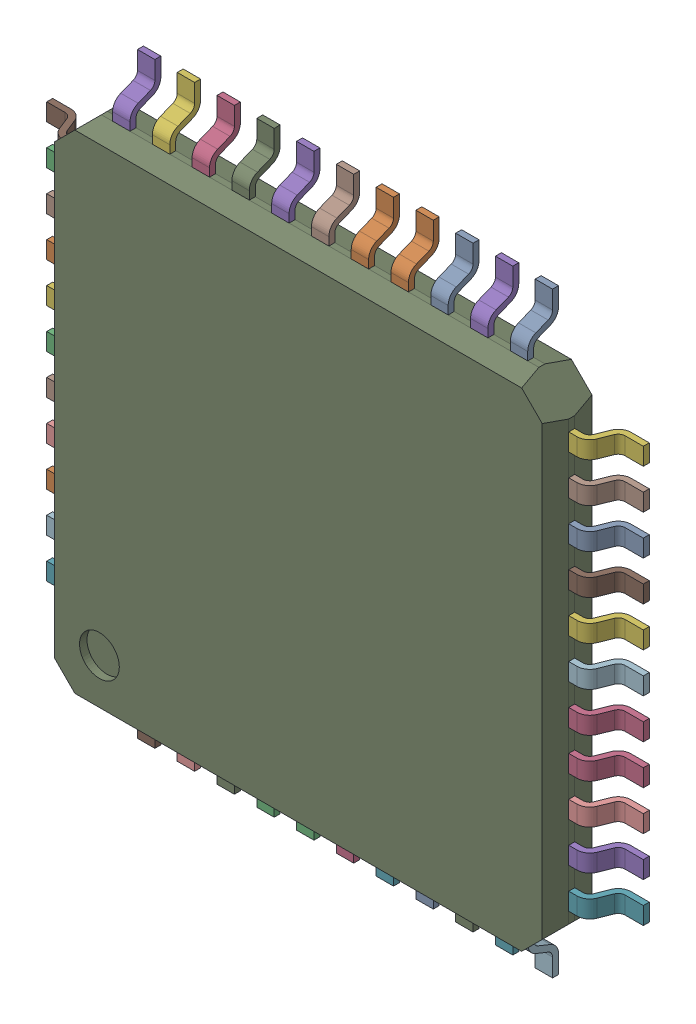
SolidWorks assembly U1, configuration Défaut. Lengths in mm.
Overall size (12 12 1.06).
46 component instances, 2 part files, 0 mates.
Components (placement in the parent):
- User_Library-TQFP-44-1: User_Library-TQFP-44 [Défaut] at (21.4631 42.8961 0.55) size (12 12 1.06)
  - User_Library-TQFP-44_pins_TQFP_pin_TQFP_035_1-1: User_Library-TQFP-44_pins_TQFP_pin_TQFP_035_1 [Défaut] at (6 2.225 -0.5) x (0 1 0) z (1 0 0) size (0.35 0.62 1)
  - User_Library-TQFP-44_pins_TQFP_pin_TQFP_035_1-2: User_Library-TQFP-44_pins_TQFP_pin_TQFP_035_1 [Défaut] at (-6 -2.225 -0.5) x (0 -1 0) z (-1 0 0) size (0.35 0.62 1)
  - User_Library-TQFP-44_pins_TQFP_pin_TQFP_035_1-3: User_Library-TQFP-44_pins_TQFP_pin_TQFP_035_1 [Défaut] at (-6 3.375 -0.5) x (0 -1 0) z (-1 0 0) size (0.35 0.62 1)
  - User_Library-TQFP-44_pins_TQFP_pin_TQFP_035_1-4: User_Library-TQFP-44_pins_TQFP_pin_TQFP_035_1 [Défaut] at (6 -0.975 -0.5) x (0 1 0) z (1 0 0) size (0.35 0.62 1)
  - User_Library-TQFP-44_pins_TQFP_pin_TQFP_035_1-5: User_Library-TQFP-44_pins_TQFP_pin_TQFP_035_1 [Défaut] at (3.375 6 -0.5) x (-1 0 0) z (0 1 0) size (0.35 0.62 1)
  - User_Library-TQFP-44_pins_TQFP_pin_TQFP_035_1-6: User_Library-TQFP-44_pins_TQFP_pin_TQFP_035_1 [Défaut] at (-6 0.975 -0.5) x (0 -1 0) z (-1 0 0) size (0.35 0.62 1)
  - User_Library-TQFP-44_pins_TQFP_pin_TQFP_035_1-7: User_Library-TQFP-44_pins_TQFP_pin_TQFP_035_1 [Défaut] at (0.625 -6 -0.5) x (1 0 0) z (0 -1 0) size (0.35 0.62 1)
  - User_Library-TQFP-44_pins_TQFP_pin_TQFP_035_1-8: User_Library-TQFP-44_pins_TQFP_pin_TQFP_035_1 [Défaut] at (0.175 6 -0.5) x (-1 0 0) z (0 1 0) size (0.35 0.62 1)
  - User_Library-TQFP-44_pins_TQFP_pin_TQFP_035_1-9: User_Library-TQFP-44_pins_TQFP_pin_TQFP_035_1 [Défaut] at (-2.575 -6 -0.5) x (1 0 0) z (0 -1 0) size (0.35 0.62 1)
  - User_Library-TQFP-44_pins_TQFP_pin_TQFP_035_1-10: User_Library-TQFP-44_pins_TQFP_pin_TQFP_035_1 [Défaut] at (-3.375 -6 -0.5) x (1 0 0) z (0 -1 0) size (0.35 0.62 1)
  - User_Library-TQFP-44_pins_TQFP_pin_TQFP_035_1-11: User_Library-TQFP-44_pins_TQFP_pin_TQFP_035_1 [Défaut] at (6 1.425 -0.5) x (0 1 0) z (1 0 0) size (0.35 0.62 1)
  - User_Library-TQFP-44_pins_TQFP_pin_TQFP_035_1-12: User_Library-TQFP-44_pins_TQFP_pin_TQFP_035_1 [Défaut] at (-6 -3.025 -0.5) x (0 -1 0) z (-1 0 0) size (0.35 0.62 1)
  - User_Library-TQFP-44_pins_TQFP_pin_TQFP_035_1-13: User_Library-TQFP-44_pins_TQFP_pin_TQFP_035_1 [Défaut] at (2.575 6 -0.5) x (-1 0 0) z (0 1 0) size (0.35 0.62 1)
  - User_Library-TQFP-44_pins_TQFP_pin_TQFP_035_1-14: User_Library-TQFP-44_pins_TQFP_pin_TQFP_035_1 [Défaut] at (1.775 6 -0.5) x (-1 0 0) z (0 1 0) size (0.35 0.62 1)
  - User_Library-TQFP-44_pins_TQFP_pin_TQFP_035_1-15: User_Library-TQFP-44_pins_TQFP_pin_TQFP_035_1 [Défaut] at (-0.975 -6 -0.5) x (1 0 0) z (0 -1 0) size (0.35 0.62 1)
  - User_Library-TQFP-44_pins_TQFP_pin_TQFP_035_1-16: User_Library-TQFP-44_pins_TQFP_pin_TQFP_035_1 [Défaut] at (-0.175 -6 -0.5) x (1 0 0) z (0 -1 0) size (0.35 0.62 1)
  - User_Library-TQFP-44_pins_TQFP_pin_TQFP_035_1-17: User_Library-TQFP-44_pins_TQFP_pin_TQFP_035_1 [Défaut] at (-0.625 6 -0.5) x (-1 0 0) z (0 1 0) size (0.35 0.62 1)
  - User_Library-TQFP-44_pins_TQFP_pin_TQFP_035_1-18: User_Library-TQFP-44_pins_TQFP_pin_TQFP_035_1 [Défaut] at (-3.025 6 -0.5) x (-1 0 0) z (0 1 0) size (0.35 0.62 1)
  - User_Library-TQFP-44_pins_TQFP_pin_TQFP_035_1-19: User_Library-TQFP-44_pins_TQFP_pin_TQFP_035_1 [Défaut] at (6 -4.175 -0.5) x (0 1 0) z (1 0 0) size (0.35 0.62 1)
  - User_Library-TQFP-44_pins_TQFP_pin_TQFP_035_1-20: User_Library-TQFP-44_pins_TQFP_pin_TQFP_035_1 [Défaut] at (6 3.025 -0.5) x (0 1 0) z (1 0 0) size (0.35 0.62 1)
  - User_Library-TQFP-44_pins_TQFP_pin_TQFP_035_1-21: User_Library-TQFP-44_pins_TQFP_pin_TQFP_035_1 [Défaut] at (2.225 -6 -0.5) x (1 0 0) z (0 -1 0) size (0.35 0.62 1)
  - User_Library-TQFP-44_pins_TQFP_pin_TQFP_035_1-22: User_Library-TQFP-44_pins_TQFP_pin_TQFP_035_1 [Défaut] at (-6 -1.425 -0.5) x (0 -1 0) z (-1 0 0) size (0.35 0.62 1)
  - User_Library-TQFP-44_pins_TQFP_pin_TQFP_035_1-23: User_Library-TQFP-44_pins_TQFP_pin_TQFP_035_1 [Défaut] at (-6 4.175 -0.5) x (0 -1 0) z (-1 0 0) size (0.35 0.62 1)
  - User_Library-TQFP-44_pins_TQFP_pin_TQFP_035_1-24: User_Library-TQFP-44_pins_TQFP_pin_TQFP_035_1 [Défaut] at (6 -0.175 -0.5) x (0 1 0) z (1 0 0) size (0.35 0.62 1)
  - User_Library-TQFP-44_pins_TQFP_pin_TQFP_035_1-25: User_Library-TQFP-44_pins_TQFP_pin_TQFP_035_1 [Défaut] at (4.175 6 -0.5) x (-1 0 0) z (0 1 0) size (0.35 0.62 1)
  - User_Library-TQFP-44_pins_TQFP_pin_TQFP_035_1-26: User_Library-TQFP-44_pins_TQFP_pin_TQFP_035_1 [Défaut] at (-6 1.775 -0.5) x (0 -1 0) z (-1 0 0) size (0.35 0.62 1)
  - User_Library-TQFP-44_pins_TQFP_pin_TQFP_035_1-27: User_Library-TQFP-44_pins_TQFP_pin_TQFP_035_1 [Défaut] at (-6 0.175 -0.5) x (0 -1 0) z (-1 0 0) size (0.35 0.62 1)
  - User_Library-TQFP-44_pins_TQFP_pin_TQFP_035_1-28: User_Library-TQFP-44_pins_TQFP_pin_TQFP_035_1 [Défaut] at (6 -1.775 -0.5) x (0 1 0) z (1 0 0) size (0.35 0.62 1)
  - User_Library-TQFP-44_pins_TQFP_pin_TQFP_035_1-29: User_Library-TQFP-44_pins_TQFP_pin_TQFP_035_1 [Défaut] at (-3.825 6 -0.5) x (-1 0 0) z (0 1 0) size (0.35 0.62 1)
  - User_Library-TQFP-44_pins_TQFP_pin_TQFP_035_1-30: User_Library-TQFP-44_pins_TQFP_pin_TQFP_035_1 [Défaut] at (6 0.625 -0.5) x (0 1 0) z (1 0 0) size (0.35 0.62 1)
  - User_Library-TQFP-44_pins_TQFP_pin_TQFP_035_1-31: User_Library-TQFP-44_pins_TQFP_pin_TQFP_035_1 [Défaut] at (-6 -3.825 -0.5) x (0 -1 0) z (-1 0 0) size (0.35 0.62 1)
  - User_Library-TQFP-44_pins_TQFP_pin_TQFP_035_1-32: User_Library-TQFP-44_pins_TQFP_pin_TQFP_035_1 [Défaut] at (-6 2.575 -0.5) x (0 -1 0) z (-1 0 0) size (0.35 0.62 1)
  - User_Library-TQFP-44_pins_TQFP_pin_TQFP_035_1-33: User_Library-TQFP-44_pins_TQFP_pin_TQFP_035_1 [Défaut] at (-1.425 6 -0.5) x (-1 0 0) z (0 1 0) size (0.35 0.62 1)
  - User_Library-TQFP-44_pins_TQFP_pin_TQFP_035_1-34: User_Library-TQFP-44_pins_TQFP_pin_TQFP_035_1 [Défaut] at (6 -2.575 -0.5) x (0 1 0) z (1 0 0) size (0.35 0.62 1)
  - User_Library-TQFP-44_pins_TQFP_pin_TQFP_035_1-35: User_Library-TQFP-44_pins_TQFP_pin_TQFP_035_1 [Défaut] at (-4.175 -6 -0.5) x (1 0 0) z (0 -1 0) size (0.35 0.62 1)
  - User_Library-TQFP-44_pins_TQFP_pin_TQFP_035_1-36: User_Library-TQFP-44_pins_TQFP_pin_TQFP_035_1 [Défaut] at (3.825 -6 -0.5) x (1 0 0) z (0 -1 0) size (0.35 0.62 1)
  - User_Library-TQFP-44_pins_TQFP_pin_TQFP_035_1-37: User_Library-TQFP-44_pins_TQFP_pin_TQFP_035_1 [Défaut] at (1.425 -6 -0.5) x (1 0 0) z (0 -1 0) size (0.35 0.62 1)
  - User_Library-TQFP-44_pins_TQFP_pin_TQFP_035_1-38: User_Library-TQFP-44_pins_TQFP_pin_TQFP_035_1 [Défaut] at (0.975 6 -0.5) x (-1 0 0) z (0 1 0) size (0.35 0.62 1)
  - User_Library-TQFP-44_pins_TQFP_pin_TQFP_035_1-39: User_Library-TQFP-44_pins_TQFP_pin_TQFP_035_1 [Défaut] at (-1.775 -6 -0.5) x (1 0 0) z (0 -1 0) size (0.35 0.62 1)
  - User_Library-TQFP-44_pins_TQFP_pin_TQFP_035_1-40: User_Library-TQFP-44_pins_TQFP_pin_TQFP_035_1 [Défaut] at (-2.225 6 -0.5) x (-1 0 0) z (0 1 0) size (0.35 0.62 1)
  - User_Library-TQFP-44_pins_TQFP_pin_TQFP_035_1-41: User_Library-TQFP-44_pins_TQFP_pin_TQFP_035_1 [Défaut] at (6 -3.375 -0.5) x (0 1 0) z (1 0 0) size (0.35 0.62 1)
  - User_Library-TQFP-44_pins_TQFP_pin_TQFP_035_1-42: User_Library-TQFP-44_pins_TQFP_pin_TQFP_035_1 [Défaut] at (6 3.825 -0.5) x (0 1 0) z (1 0 0) size (0.35 0.62 1)
  - User_Library-TQFP-44_pins_TQFP_pin_TQFP_035_1-43: User_Library-TQFP-44_pins_TQFP_pin_TQFP_035_1 [Défaut] at (3.025 -6 -0.5) x (1 0 0) z (0 -1 0) size (0.35 0.62 1)
  - User_Library-TQFP-44_pins_TQFP_pin_TQFP_035_1-44: User_Library-TQFP-44_pins_TQFP_pin_TQFP_035_1 [Défaut] at (-6 -0.625 -0.5) x (0 -1 0) z (-1 0 0) size (0.35 0.62 1)
  - User_Library-TQFP-44_body_10x1_TQFP_10x10_1-1: User_Library-TQFP-44_body_10x1_TQFP_10x10_1 [Défaut] at (0 0 -0.5) size (10 10 1)
